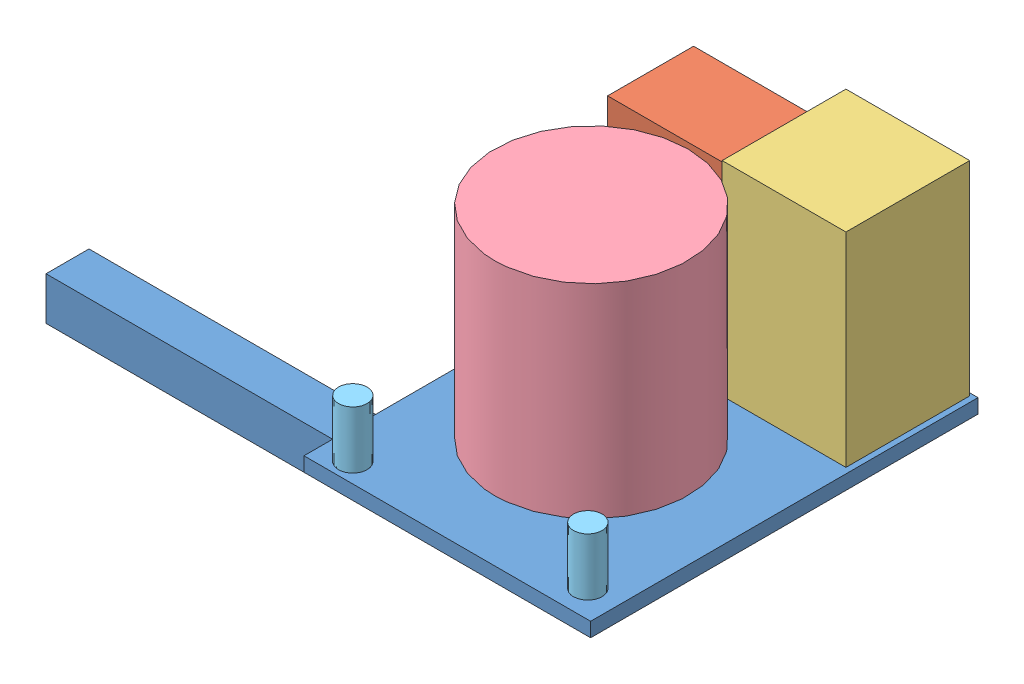
SolidWorks assembly GN&C_assem, configuration Default. Lengths in mm.
Overall size (480 252.24 270.29).
6 component instances, 5 part files, 5 mates.
Components (placement in the parent):
- mount-1: mount [Default] at origin size (480 110 270.29)
- descent imager-1: descent imager [Default] at (-111.5702 10 -203.4147) size (80 120 60)
- Radar Altimeter-1: Radar Altimeter [Default] at (-90.262 10 -182.0396) size (86.36 142.24 86.36)
- Star Tracker-1: Star Tracker [Default] at (-109.408 10 -109.8916) size (135 142 135)
- sun sensor_2-1: sun sensor_2 [Default] at (-20.8013 10 -18.8431) x (0.996981 0 0.07765) z (-0.07765 0 0.996981) size (20 40 20)
- sun sensor_2-2: sun sensor_2 [Default] at (-179.5135 10 -13.6063) size (20 40 20)
Mates (geometry in assembly coordinates):
- Coincident1: coincident anti-aligned: plane of mount-1 through (0 10 -270.2852) normal (0 1 0); plane of Star Tracker-1 through (-109.408 10 -109.8916) normal (0 -1 0)
- Coincident2: coincident anti-aligned: plane of mount-1 through (0 10 -270.2852) normal (0 1 0); plane of sun sensor_2-2 through (-179.5135 10 -13.6063) normal (0 -1 0)
- Coincident3: coincident aligned: plane of mount-1 through (0 10 -270.2852) normal (0 1 0); circle of sun sensor_2-1 centre (-20.8013 10 -18.8431) axis (0 1 0)
- Coincident4: coincident anti-aligned: plane of mount-1 through (0 10 -270.2852) normal (0 1 0); plane of descent imager-1 through (-111.5702 10 -263.4147) normal (0 -1 0)
- Coincident5: coincident anti-aligned: plane of mount-1 through (0 10 -270.2852) normal (0 1 0); plane of Radar Altimeter-1 through (-90.262 10 -268.3996) normal (0 -1 0)
